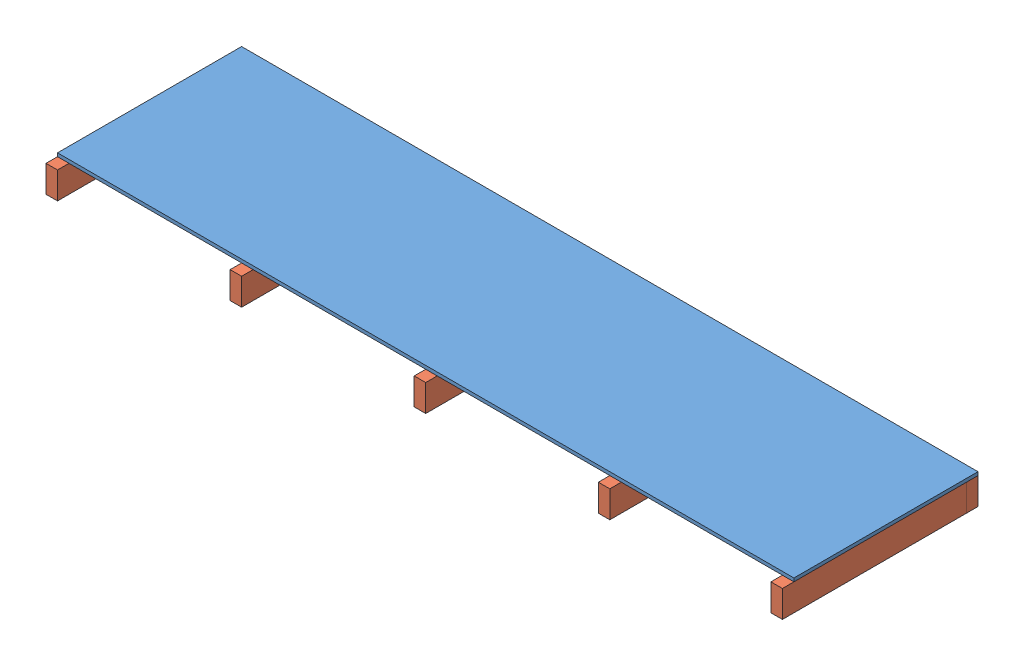
SolidWorks assembly Shelf, configuration Default. Lengths in mm.
Overall size (2438.4 100.01 647.7).
7 component instances, 2 part files, 9 mates.
Components (placement in the parent):
- Plywood-1: Plywood [2ftX8ft] at (2465.4186 472.2515 -308.2621) x (0 0 1) z (0 -1 0) size (609.6 2438.4 11.11)
- 2x4-6: 2x4 [8ft] at (27.0186 372.239 -308.2621) x (0 1 0) z (1 0 0) size (88.9 38.1 2438.4)
- 2x4-7: 2x4 [2ft] at (65.1186 372.239 -270.1621) x (0 1 0) z (0 0 1) size (88.9 38.1 609.6)
- 2x4-9: 2x4 [2ft] at (674.7186 372.239 -270.1621) x (0 1 0) z (0 0 1) size (88.9 38.1 609.6)
- 2x4-10: 2x4 [2ft] at (1284.3186 372.239 -270.1621) x (0 1 0) z (0 0 1) size (88.9 38.1 609.6)
- 2x4-11: 2x4 [2ft] at (1893.9186 372.239 -270.1621) x (0 1 0) z (0 0 1) size (88.9 38.1 609.6)
- 2x4-12: 2x4 [2ft] at (2427.3186 461.139 -270.1621) x (0 -1 0) z (0 0 1) size (88.9 38.1 609.6)
Mates (geometry in assembly coordinates):
- Coincident1: coincident anti-aligned: plane of Plywood-1 through (2465.4186 461.139 -308.2621) normal (0 -1 0); plane of 2x4-6 through (2465.4186 461.139 -308.2621) normal (0 1 0)
- Coincident2: coincident aligned: plane of Plywood-1 through (2465.4186 461.139 -308.2621) normal (0 0 -1); plane of 2x4-6 through (2465.4186 372.239 -308.2621) normal (0 0 -1)
- Coincident3: coincident aligned: plane of Plywood-1 through (2465.4186 461.139 -308.2621) normal (1 0 0); plane of 2x4-6 through (2465.4186 372.239 -308.2621) normal (1 0 0)
- Coincident4: coincident anti-aligned: plane of Plywood-1 through (2465.4186 461.139 -308.2621) normal (0 -1 0); plane of 2x4-7 through (65.1186 461.139 339.4379) normal (0 1 0)
- Coincident5: coincident aligned: plane of Plywood-1 through (27.0186 461.139 -308.2621) normal (-1 0 0); plane of 2x4-7 through (27.0186 372.239 339.4379) normal (-1 0 0)
- Coincident6: coincident anti-aligned: plane of 2x4-6 through (2465.4186 372.239 -270.1621) normal (0 0 1); plane of 2x4-7 through (65.1186 372.239 -270.1621) normal (0 0 -1)
- Coincident7: coincident aligned: plane of Plywood-1 through (2465.4186 461.139 -308.2621) normal (1 0 0); plane of 2x4-12 through (2465.4186 461.139 339.4379) normal (1 0 0)
- Coincident8: coincident anti-aligned: plane of Plywood-1 through (2465.4186 461.139 -308.2621) normal (0 -1 0); plane of 2x4-12 through (2427.3186 461.139 339.4379) normal (0 1 0)
- Coincident9: coincident anti-aligned: plane of 2x4-6 through (2465.4186 372.239 -270.1621) normal (0 0 1); plane of 2x4-12 through (2427.3186 461.139 -270.1621) normal (0 0 -1)
